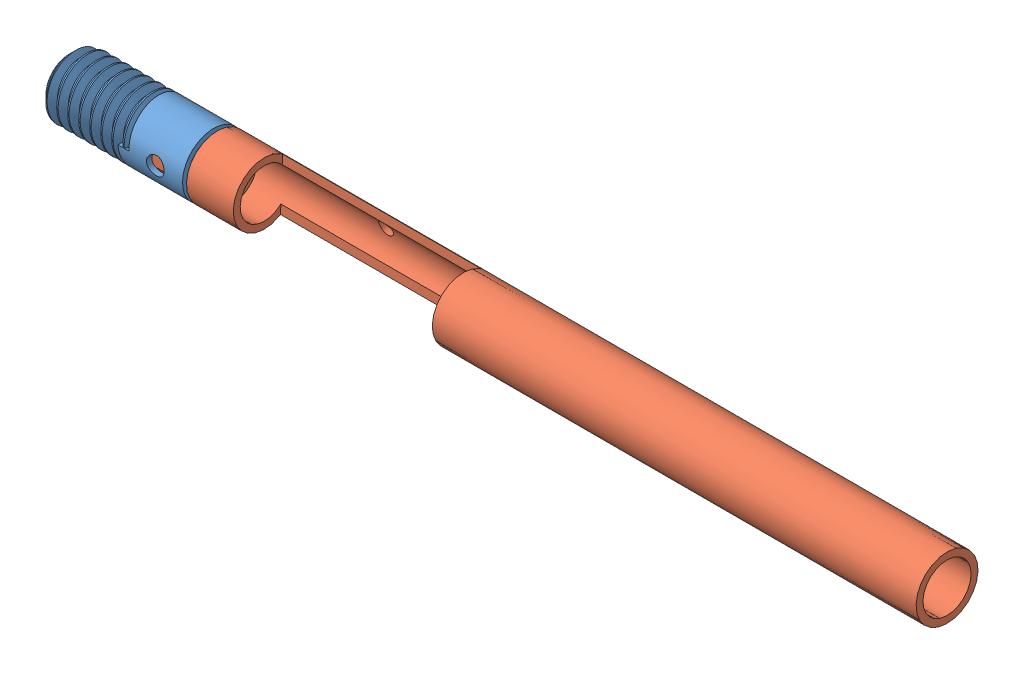
SolidWorks assembly Assem1, configuration Default. Lengths in mm.
Overall size (112.88 8.25 8.26).
2 component instances, 2 part files, 2 mates.
Components (placement in the parent):
- wheel_handle_body_A v-2 20-Mar-2017-1: wheel_handle_body_A v-2 20-Mar-2017 [Default] at (7.7079 20.7035 32.1628) size (38.13 7.99 8.1)
- wheel_handle_body_B v-2 20-Mar-2017-2: wheel_handle_body_B v-2 20-Mar-2017 [Default] at (8.2079 20.7035 32.1628) x (1 0 0) z (0 0.040313 0.999187) size (100.5 7.94 7.94)
Mates (geometry in assembly coordinates):
- Concentric2: concentric anti-aligned: circle of wheel_handle_body_A v-2 20-Mar-2017-1; circle of wheel_handle_body_B v-2 20-Mar-2017-2
- Coincident1: coincident anti-aligned: plane of wheel_handle_body_A v-2 20-Mar-2017-1 through (7.7079 20.7035 32.1628) normal (1 0 0); plane of wheel_handle_body_B v-2 20-Mar-2017-2 through (7.7079 20.7035 32.1628) normal (-1 0 0)
